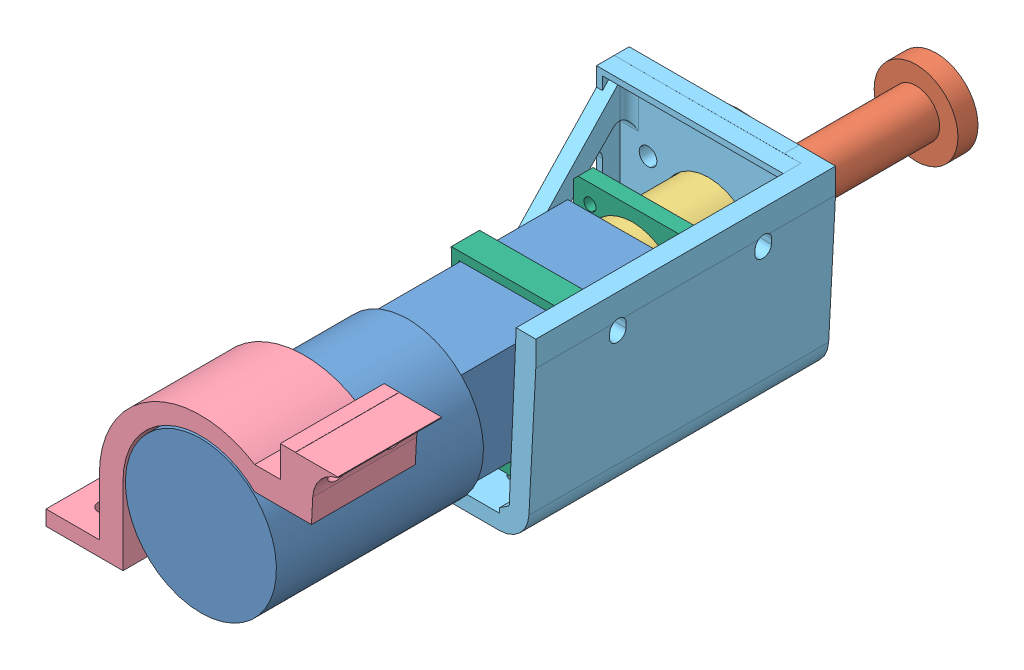
SolidWorks assembly D-01-00-F, configuration Default. Lengths in mm.
Overall size (236.27 86.37 311.5).
8 component instances, 7 part files, 10 mates.
Components (placement in the parent):
- S-01-01-01-1: S-01-01-01 [Default] at (62.5689 370.838 601.9542) size (658.2 105 450) (hidden)
- D-01-04-1: D-01-04 [Default] at (-200.2787 486.0655 434.0158) x (0 0 -1) z (0.003816 -0.999993 0) size (311.5 78.45 78.45)
  - moteur_pla_simplifie-2: moteur_pla_simplifie [Default] at (-156.9384 51.1827 137.4238) size (176.5 64 64)
  - moteur_axe_pla_simplifie-1: moteur_axe_pla_simplifie [Default] at (3.5616 51.1827 137.4238) size (151 35.5 35.5)
  - front_housing_moteur_pla_simplifie-2: front_housing_moteur_pla_simplifie [Default] at (64.5616 51.1827 137.4238) x (1 0 0) z (0 0.00581 0.999983) size (60 78 78)
- D-01-01-1: D-01-01 [Default] at (-148.5686 348.838 546.9542) x (-1 0 0) z (0 0 -1) size (123.62 80 44)
- D-01-02-F-1: D-01-02-F [Default] at (-188.5719 315.838 369.4542) x (0 0 1) z (-1 0 0) size (205.75 78 225.67)
- D-01-03-F-1: D-01-03-F [Default] at (-201.2804 326.6367 401.8176) x (0 0 1) z (0.003816 -0.999993 0) size (78.5 97.78 66.5)
Mates (geometry in assembly coordinates):
- Coincident1: coincident anti-aligned: line of S-01-01-01-1 through (-116.5719 315.838 376.9542) axis (0 0 1); line of D-01-02-F-1 through (-116.5719 315.838 496.4542) axis (0 0 -1)
- Coincident2: coincident anti-aligned: plane of S-01-01-01-1 through (-104.0891 327.6838 376.9542) normal (-0.99863 0.052336 0); plane of D-01-02-F-1 through (-101.1877 383.0446 455.3068) normal (0.99863 -0.052336 0)
- Distance1: distance = 7.5 mm aligned: plane of D-01-02-F-1 through (-268.5719 315.838 369.4542) normal (0 0 -1); plane of S-01-01-01-1 through (-116.5719 328.338 376.9542) normal (0 0 -1)
- Coincident4: coincident anti-aligned: plane of D-01-02-F-1 through (-109.4865 393.7976 575.9172) normal (-0.999026 0.044132 0); plane of D-01-03-F-1 through (-110.3839 373.484 401.8166) normal (0.999026 -0.044132 0)
- Coincident6: coincident anti-aligned: plane of S-01-01-01-1 through (-266.5311 315.838 376.9542) normal (0 1 0); plane of D-01-01-1 through (-181.5719 315.838 590.9542) normal (0 -1 0)
- Concentric1: concentric anti-aligned: cylinder of D-01-04-1/moteur_pla_simplifie-2 through (-148.5719 348.838 503.2342) axis (0 0 1) radius 32; cylinder of D-01-01-1 through (-148.5719 348.838 590.9542) axis (0 0 -1) radius 33
- Coincident7: coincident anti-aligned: plane of D-01-04-1/front_housing_moteur_pla_simplifie-2 through (-148.5719 348.838 369.4542) normal (0 0 1); plane of D-01-02-F-1 through (-268.5719 315.838 369.4542) normal (0 0 -1)
- Concentric2: concentric aligned: cylinder of D-01-04-1/moteur_axe_pla_simplifie-1 through (-148.5719 348.838 287.9542) axis (0 0 1) radius 10; cylinder of D-01-02-F-1 through (-148.5719 348.838 369.4532) axis (0 0 1) radius 20.25
- Coincident9: coincident anti-aligned: plane of D-01-04-1/moteur_pla_simplifie-2 through (-127.6522 369.918 414.4542) normal (-0.003816 0.999993 0); plane of D-01-03-F-1 through (-97.9418 370.0314 447.8776) normal (0.003816 -0.999993 0)
- Coincident10: coincident aligned: plane of D-01-04-1/moteur_pla_simplifie-2 through (-148.5719 348.838 590.9542) normal (0 0 1); plane of D-01-01-1 through (-148.699 346.4685 590.9542) normal (0 0 1)
